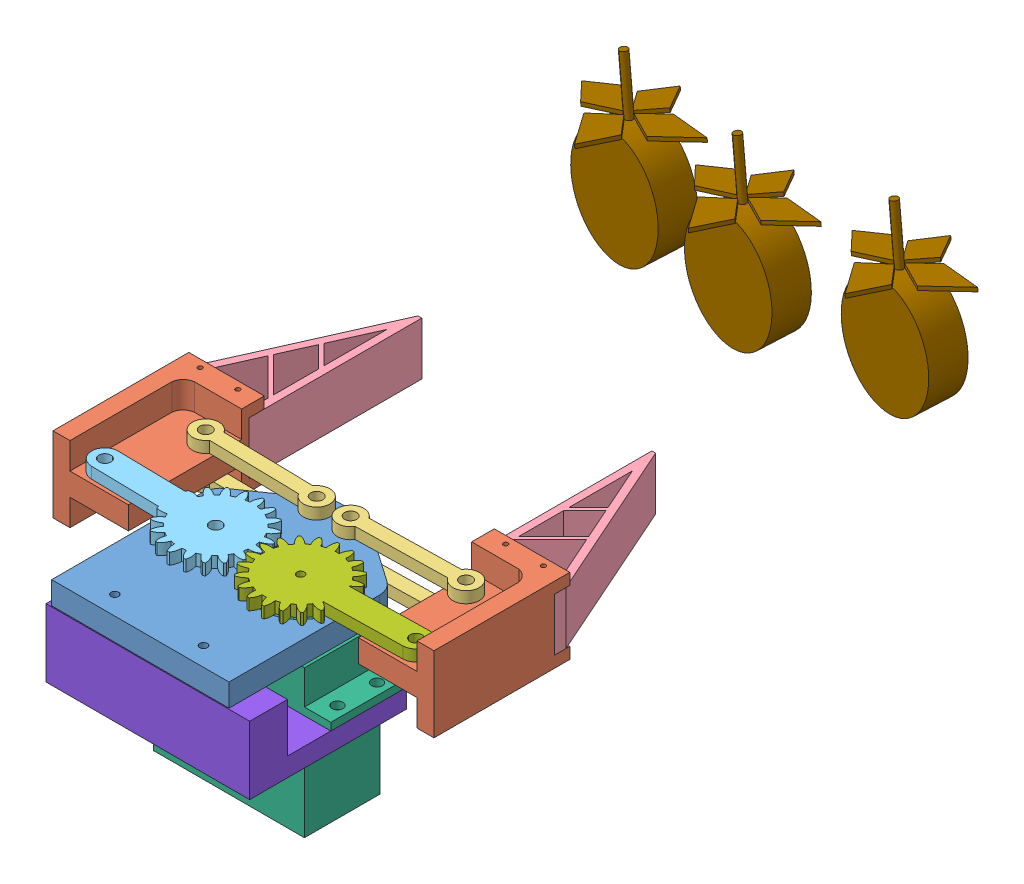
SolidWorks assembly keepv.2, configuration Default. Lengths in mm.
Overall size (116.58 97.95 170.64).
16 component instances, 9 part files, 35 mates.
Components (placement in the parent):
- basekeep-1: basekeep [Default] at (15.4682 14.9446 43.682) size (47 6 55.75)
- handw.2-1: handw.2 [Default] at (55.9623 17.9446 8.8383) x (0 0 1) z (-1 0 0) size (36 20 20)
- arm1-1: arm1 [Default] at (19.9682 20.9446 2.432) x (0.999804 0 -0.019791) z (0.019791 0 0.999804) size (37 3 7)
- finger-1: finger [Default] at (55.6803 24.9446 -31.7963) x (-1 0 0) z (0 0 1) size (20 14 45.75)
- arm1-2: arm1 [Default] at (-19.0259 20.9446 1.8383) x (0.999804 0 0.019791) z (-0.019791 0 0.999804) size (37 3 7)
- handw.2-2: handw.2 [Default] at (-25.0259 17.9446 8.8383) x (0 0 1) z (1 0 0) size (36 20 20)
- finger-2: finger [Default] at (-24.7439 10.9446 -31.7963) size (20 14 45.75)
- arm1-3: arm1 [Default] at (19.9682 11.9446 2.432) x (0.999804 0 -0.019791) z (0.019791 0 0.999804) size (37 3 7)
- arm1-4: arm1 [Default] at (-19.0259 11.9446 1.8383) x (0.999804 0 0.019791) z (-0.019791 0 0.999804) size (37 3 7)
- Gear1left-1: Gear1left [Default] at (4.8809 30.294 22.913) x (0 1 0) z (-0.990591 0 0.136857) size (3 24.53 45.4)
- servonew-1: servonew [Default] at (17.7182 -26.0554 22.432) size (54 47 21)
- gear2mm.20-1: gear2mm.20 [Default] at (26.1389 14.5952 23.0107) x (0 -1 0) z (0.999804 0 -0.019791) size (3 24.53 45.76)
- servopart1-1: servopart1 [Default] at (17.7182 -3.0554 33.182) size (54 18 41.5)
- STW-1: STW [Default] at (29.1944 36.9418 -93.6464) x (-0.101269 0.994826 -0.00816) z (-0.993845 -0.101533 -0.044299) size (44.98 27.55 33.21)
- STW-2: STW [Default] at (-1.9212 40.1834 -94.6026) x (-0.101269 0.994826 -0.00816) z (-0.993845 -0.101533 -0.044299) size (44.98 27.55 33.21)
- STW-3: STW [Default] at (61.7015 33.63 -102.6833) x (-0.101269 0.994826 -0.00816) z (-0.993845 -0.101533 -0.044299) size (44.98 27.55 33.21)
Mates (geometry in assembly coordinates):
- Concentric1: concentric aligned: cylinder of basekeep-1 through (19.9682 20.9446 2.432) axis (0 -1 0) radius 1.6; cylinder of arm1-1 through (19.9682 23.9446 2.432) axis (0 -1 0) radius 1.6
- Coincident1: coincident anti-aligned: plane of basekeep-1 through (15.4682 20.9446 43.682) normal (0 1 0); plane of arm1-1 through (19.9682 20.9446 2.432) normal (0 -1 0)
- Concentric5: concentric aligned: cylinder of basekeep-1 through (10.9682 20.9446 2.432) axis (0 -1 0) radius 1.6; cylinder of arm1-2 through (10.9682 23.9446 2.432) axis (0 -1 0) radius 1.6
- Coincident5: coincident anti-aligned: plane of basekeep-1 through (15.4682 20.9446 43.682) normal (0 1 0); plane of arm1-2 through (-19.0259 20.9446 1.8383) normal (0 -1 0)
- Concentric9: concentric anti-aligned: cylinder of handw.2-1 through (49.9623 13.9446 1.8383) axis (0 1 0) radius 1.6; cylinder of arm1-1 through (49.9623 23.9446 1.8383) axis (0 -1 0) radius 1.6
- Coincident8: coincident anti-aligned: plane of handw.2-1 through (57.6704 20.9446 0.1302) normal (0 1 0); plane of arm1-1 through (19.9682 20.9446 2.432) normal (0 -1 0)
- Concentric11: concentric aligned: cylinder of arm1-2 through (-19.0259 23.9446 1.8383) axis (0 -1 0) radius 1.6; cylinder of handw.2-2 through (-19.0259 21.9446 1.8383) axis (0 -1 0) radius 1.6
- Coincident9: coincident anti-aligned: plane of arm1-2 through (-19.0259 20.9446 1.8383) normal (0 -1 0); plane of handw.2-2 through (-27.1606 20.9446 -0.2963) normal (0 1 0)
- Concentric13: concentric aligned: cylinder of basekeep-1 through (10.9682 20.9446 2.432) axis (0 -1 0) radius 1.6; cylinder of arm1-4 through (10.9682 14.9446 2.432) axis (0 -1 0) radius 1.6
- Concentric14: concentric aligned: cylinder of handw.2-2 through (-19.0259 21.9446 1.8383) axis (0 -1 0) radius 1.6; cylinder of arm1-4 through (-19.0259 14.9446 1.8383) axis (0 -1 0) radius 1.6
- Coincident18: coincident anti-aligned: plane of handw.2-2 through (-26.734 14.9446 0.1302) normal (0 -1 0); plane of arm1-4 through (-19.0259 14.9446 1.8383) normal (0 1 0)
- Concentric16: concentric anti-aligned: cylinder of handw.2-1 through (49.9623 13.9446 1.8383) axis (0 1 0) radius 1.6; cylinder of arm1-3 through (49.9623 14.9446 1.8383) axis (0 -1 0) radius 1.6
- Coincident20: coincident anti-aligned: plane of handw.2-1 through (58.097 14.9446 -0.2963) normal (0 -1 0); plane of arm1-3 through (19.9682 14.9446 2.432) normal (0 1 0)
- Concentric17: concentric aligned: cylinder of basekeep-1 through (19.9682 20.9446 2.432) axis (0 -1 0) radius 1.6; cylinder of arm1-3 through (19.9682 14.9446 2.432) axis (0 -1 0) radius 1.6
- Coincident23: coincident anti-aligned: plane of basekeep-1 through (15.4682 20.9446 43.682) normal (0 1 0); plane of Gear1left-1 through (4.2182 20.9446 22.432) normal (0 -1 0)
- Concentric20: concentric anti-aligned: cylinder of handw.2-2 through (-25.7759 21.9446 21.8383) axis (0 -1 0) radius 1.6; cylinder of Gear1left-1 through (-25.7759 20.9446 21.8383) axis (0 1 0) radius 1.6
- Concentric21: concentric anti-aligned: cylinder of handw.2-1 through (56.7123 13.9446 21.8383) axis (0 1 0) radius 1.6; cylinder of gear2mm.20-1 through (56.7123 23.9446 21.8383) axis (0 -1 0) radius 1.6
- Coincident24: coincident anti-aligned: plane of handw.2-1 through (57.6704 20.9446 0.1302) normal (0 1 0); plane of gear2mm.20-1 through (26.7182 20.9446 22.432) normal (0 -1 0)
- Concentric22: concentric aligned: cylinder of basekeep-1 through (26.7182 20.9446 22.432) axis (0 -1 0) radius 10.5; cylinder of gear2mm.20-1 through (26.7182 23.9446 22.432) axis (0 -1 0) radius 1
- GearMate1: gear = 1 : 1 mm: cylinder of gear2mm.20-1 through (26.7182 20.9446 22.432) axis (0 1 0) radius 9.8428; cylinder of Gear1left-1 through (4.2182 23.9446 22.432) axis (0 -1 0) radius 9.8428
- Concentric24: concentric aligned: cylinder of basekeep-1 through (26.7182 20.9446 22.432) axis (0 -1 0) radius 10.5; cylinder of servonew-1 through (26.7182 20.9446 22.432) axis (0 -1 0) radius 10.5
- Coincident25: coincident anti-aligned: plane of handw.2-1 through (55.9623 17.9446 -5.6617) normal (0 0 -1); plane of finger-1 through (65.9623 10.9446 -5.6617) normal (0 0 1)
- Coincident26: coincident anti-aligned: plane of handw.2-2 through (-25.0259 17.9446 -5.6617) normal (0 0 -1); plane of finger-2 through (-35.0259 24.9446 -5.6617) normal (0 0 1)
- Coincident27: coincident aligned: line of handw.2-2 through (-15.0259 24.9446 -5.6617) axis (0 -1 0); line of finger-2 through (-15.0259 24.9446 -5.6617) axis (0 -1 0)
- Coincident28: coincident aligned: line of handw.2-1 through (45.9623 10.9446 -5.6617) axis (0 1 0); line of finger-1 through (45.9623 10.9446 -5.6617) axis (0 1 0)
- Concentric25: concentric aligned: cylinder of servonew-1 through (41.7182 -26.0554 17.182) axis (0 1 0) radius 1.45; cylinder of servopart1-1 through (41.7182 -3.0554 17.182) axis (0 1 0) radius 1.5
- Concentric26: concentric aligned: cylinder of servonew-1 through (-6.2818 -26.0554 17.182) axis (0 1 0) radius 1.45; cylinder of servopart1-1 through (-6.2818 -3.0554 17.182) axis (0 1 0) radius 1.5
- Coincident30: coincident anti-aligned: plane of servonew-1 through (44.7182 1.9446 32.432) normal (0 -1 0); plane of servopart1-1 through (17.7182 1.9446 33.182) normal (0 1 0)
- Coincident32: coincident anti-aligned: plane of servonew-1 through (26.7182 20.9446 22.432) normal (0 1 0); plane of gear2mm.20-1 through (26.7182 20.9446 22.432) normal (0 -1 0)
- Parallel2: parallel aligned: line of basekeep-1 through (-8.0318 14.9446 53.682) axis (1 0 0); line of servopart1-1 through (-9.2818 14.9446 53.932) axis (1 0 0)
- Coincident33: coincident anti-aligned: plane of handw.2-1 through (65.9623 24.9446 -5.6617) normal (0 -1 0); plane of finger-1 through (55.6803 24.9446 -31.7963) normal (0 1 0)
- LimitAngle3: limit planar angle = 1.590588 rad anti-aligned: plane of Gear1left-1 through (4.1489 20.9446 25.9314) normal (-0.019791 0 0.999804); plane of basekeep-1 through (-8.0318 20.9446 -2.068) normal (-1 0 0)
- LimitAngle4: limit planar angle = 1.590588 rad anti-aligned: plane of gear2mm.20-1 through (26.7875 23.9446 25.9314) normal (0.019791 0 0.999804); plane of basekeep-1 through (38.9682 20.9446 -2.068) normal (1 0 0)
- Coincident34: coincident anti-aligned: plane of handw.2-2 through (-35.0259 24.9446 -5.6617) normal (0 -1 0); plane of finger-2 through (-24.7439 24.9446 -31.7963) normal (0 1 0)
- Concentric27: concentric anti-aligned: cylinder of basekeep-1 through (4.2182 20.9446 22.432) axis (0 -1 0) radius 1.6; cylinder of Gear1left-1 through (4.2182 20.9446 22.432) axis (0 1 0) radius 1.6
